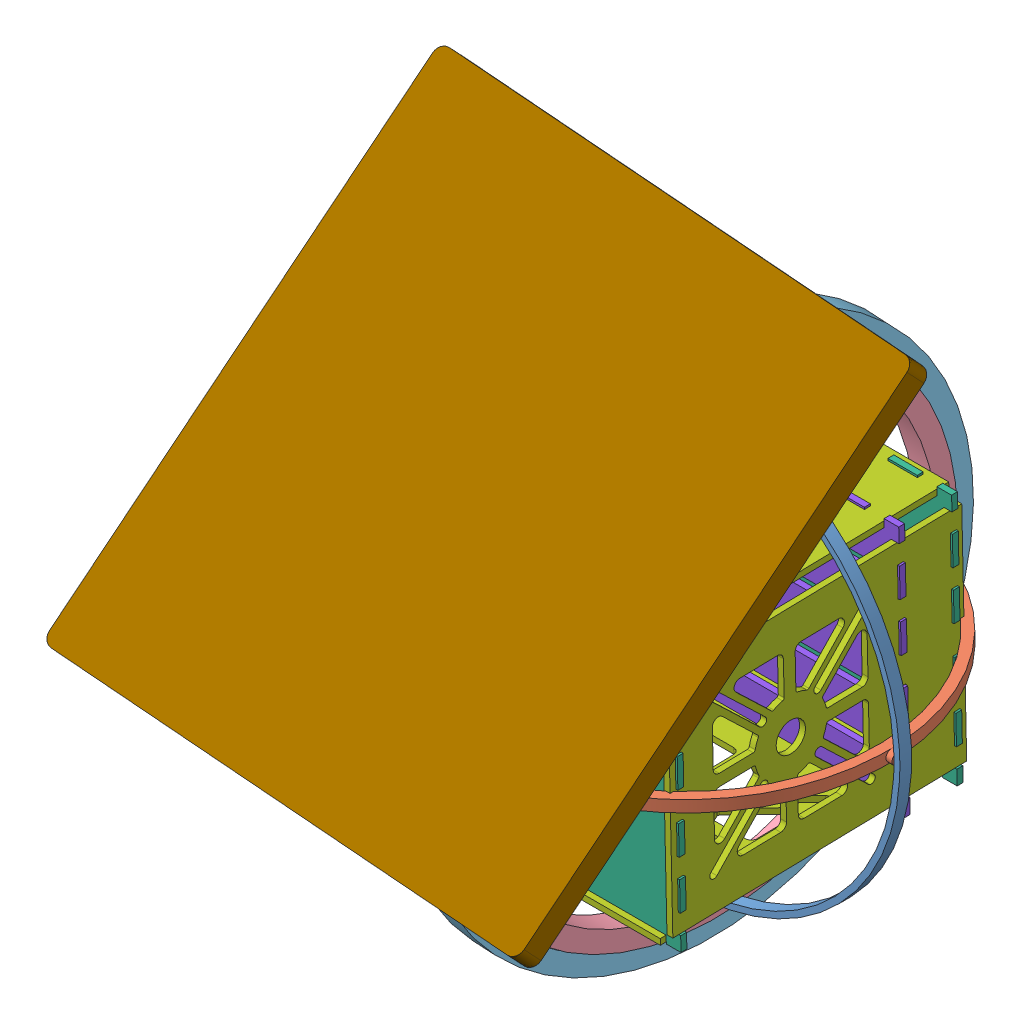
SolidWorks assembly Assem1, configuration Default. Lengths in mm.
Overall size (274.37 386.75 392.95).
17 component instances, 9 part files, 23 mates.
Components (placement in the parent):
- Part1-1: Part1 [Default] at (-77.7501 134.5326 229.0144) size (218.49 222.49 6)
- Part2-1: Part2 [Default] at (-77.7501 137.5319 232.0804) x (1 0 0) z (0 -0.999758 -0.021989) size (210.49 204.49 6)
- Part3-2: Part3 [Default] at (30.497 134.5326 232.0144) x (0 0.279636 -0.960106) z (-1 0 0) size (1 1 6)
- Part3-3: Part3 [Default] at (-179.9973 134.5326 232.0144) x (0 0.77316 -0.634211) z (-1 0 0) size (1 1 6)
- Part3-4: Part3 [Default] at (-77.7501 19.2855 232.0144) x (0.974329 0 0.225129) z (0 1 0) size (1 1 6)
- Part4-1: Part4 [Default] at (-77.7501 134.5326 232.0144) x (0.055086 0 -0.998482) z (0.998482 0 0.055086) size (246.49 246.49 12)
- Part5-1: Part5 [Default] at (-81.1914 134.5326 231.8245) x (-0.040096 -0.685716 0.726764) z (0.998482 0 0.055086) size (268.49 278.49 11.97)
- Part3-5: Part3 [Default] at (-77.7501 249.7798 232.0144) x (1 0 0) z (0 -1 0) size (1 1 6)
- final-1: final [Default] at (38.2351 129.0668 242.2567) x (0 0.999758 0.021989) z (-1 0 0) size (130 150 130)
  - shelve-1: shelve [Default] at (1.0656 79.36 115.9852) size (130 3 130)
  - sides-1: sides [Default] at (65.0656 10.36 115.9852) x (0 0 1) z (-1 0 0) size (115 150 3)
  - sides-2: sides [Default] at (-62.9344 10.36 115.9852) x (0 0 -1) z (1 0 0) size (115 150 3)
  - sides-3: sides [Default] at (1.0656 10.36 176.9852) size (115 150 3)
  - sides-4: sides [Default] at (1.0656 10.36 51.9852) size (115 150 3)
  - shelve-7: shelve [Default] at (1.0656 -61.64 115.9852) size (130 3 130)
  - shelve - Copy-1: shelve - Copy [Default] at (1.0656 52.36 115.9852) size (130 3 130)
- Part7-3: Part7 [Default] at (-86.7157 240.9814 331.9563) x (0.997727 -0.010787 0.066512) z (0.037774 -0.727869 -0.684675) size (260 260 12)
Mates (geometry in assembly coordinates):
- Concentric1: concentric: cylinder of assembly; cylinder of assembly; cylinder of Part2-1 through (27.497 134.5326 232.0144) axis (-1 0 0) radius 0.5; cylinder of Part3-2 through (24.497 134.5326 232.0144) axis (1 0 0) radius 0.5
- Coincident5: coincident: plane of assembly; circle of assembly; plane of Part1-1 through (30.497 134.5326 232.0144) normal (-1 0 0); circle of Part3-2
- Concentric9: concentric: cylinder of assembly; cylinder of assembly; cylinder of Part1-1 through (-182.9973 134.5326 232.0144) axis (-1 0 0) radius 0.5; cylinder of Part3-3 through (-185.9973 134.5326 232.0144) axis (1 0 0) radius 0.5
- Concentric10: concentric: circle of assembly; cylinder of assembly; circle of Part3-3; cylinder of Part1-1 through (-182.9973 134.5326 232.0144) axis (-1 0 0) radius 0.5
- Concentric11: concentric: circle of assembly; circle of assembly; circle of Part4-1; circle of Part5-1
- Concentric12: concentric: cylinder of assembly; cylinder of assembly; cylinder of Part1-1 through (-77.7501 245.7798 232.0144) axis (0 -1 0) radius 0.5; cylinder of Part3-5 through (-77.7501 243.7798 232.0144) axis (0 1 0) radius 0.5
- Tangent17: tangent: cylinder of assembly; plane of assembly; cylinder of Part1-1 through (-77.7501 134.5326 235.0144) axis (0 0 -1) radius 109.2472; plane of Part3-5 through (-77.7501 243.7798 232.0144) normal (0 -1 0)
- Concentric13: concentric: cylinder of assembly; cylinder of assembly; cylinder of Part1-1 through (-77.7501 23.2855 232.0144) axis (0 1 0) radius 0.5; cylinder of Part3-4 through (-77.7501 25.2855 232.0144) axis (0 -1 0) radius 0.5
- Tangent20: tangent: cylinder of assembly; plane of assembly; cylinder of Part1-1 through (-77.7501 134.5326 235.0144) axis (0 0 -1) radius 109.2472; plane of Part3-4 through (-77.7501 25.2855 232.0144) normal (0 1 0)
- Concentric14: concentric: cylinder of assembly; cylinder of assembly; cylinder of Part4-1 through (-77.7501 220.7798 232.0144) axis (0 1 0) radius 0.5; cylinder of Part3-5 through (-77.7501 243.7798 232.0144) axis (0 1 0) radius 0.5
- Concentric15: concentric: cylinder of assembly; cylinder of assembly; cylinder of Part3-4 through (-77.7501 25.2855 232.0144) axis (0 -1 0) radius 0.5; cylinder of Part4-1 through (-77.7501 30.2855 232.0144) axis (0 -1 0) radius 0.5
- Coincident6: coincident: plane of assembly; plane of assembly; plane of Part4-1 through (-77.7501 249.7798 232.0144) normal (0 -1 0); plane of Part3-5 through (-77.7501 249.7798 232.0144) normal (0 1 0)
- Tangent21: tangent: cylinder of assembly; plane of assembly; cylinder of Part2-1 through (-77.7501 131.5333 231.9484) axis (0 0.999758 0.021989) radius 102.2472; plane of Part3-2 through (24.497 134.5326 232.0144) normal (-1 0 0)
- Coincident9: coincident: plane of assembly; plane of assembly; plane of Part1-1 through (-185.9973 134.5326 232.0144) normal (1 0 0); plane of Part3-3 through (-185.9973 134.5326 232.0144) normal (-1 0 0)
- Concentric16: concentric: cylinder of assembly; cylinder of assembly; cylinder of Part2-1 through (-182.9973 134.5326 232.0144) axis (1 0 0) radius 0.5; cylinder of Part3-3 through (-185.9973 134.5326 232.0144) axis (1 0 0) radius 0.5
- Tangent22: tangent: cylinder of assembly; plane of assembly; cylinder of Part2-1 through (-77.7501 131.5333 231.9484) axis (0 0.999758 0.021989) radius 102.2472; plane of Part3-3 through (-179.9973 134.5326 232.0144) normal (1 0 0)
- Parallel2: parallel: plane of assembly; plane of assembly; plane of Part4-1 through (-71.7592 257.7798 232.3449) normal (0.998482 0 0.055086); plane of Part5-1 through (-70.5528 44.0969 147.0837) normal (0.998482 0 0.055086)
- Concentric18: concentric: cylinder of assembly; cylinder of assembly; cylinder of Part5-1 through (-86.6401 239.5257 330.5869) axis (0.037774 -0.727869 -0.684675) radius 5.975; cylinder of Part7-3 through (-86.6401 239.5257 330.5869) axis (0.037774 -0.727869 -0.684675) radius 5.795
- Coincident13: coincident: circle of assembly; plane of assembly; circle of Part5-1; plane of Part7-3 through (-86.6401 239.5257 330.5869) normal (0.037774 -0.727869 -0.684675)
- Coincident14: coincident: plane of assembly; plane of assembly; plane of Part2-1 through (-13.7501 143.1409 158.9671) normal (-1 0 0); plane of final-1/sides-4 through (-13.7501 130.36 231.9226) normal (1 0 0)
- Coincident15: coincident: plane of assembly; plane of assembly; plane of Part2-1 through (-13.7501 143.1801 157.1864) normal (0 -0.021989 0.999758); plane of final-1/sides-4 through (-16.7501 74.523 155.6764) normal (0 0.021989 -0.999758)
- Coincident16: coincident: plane of assembly; plane of assembly; plane of Part2-1 through (-141.7501 139.9209 305.3695) normal (1 0 0); plane of final-1/sides-3 through (-141.7501 130.36 231.9226) normal (-1 0 0)
- Coincident17: coincident: plane of assembly; plane of assembly; plane of Part2-1 through (-141.7501 139.8817 307.1502) normal (0 0.021989 -0.999758); plane of final-1/sides-3 through (-141.7501 71.2247 305.6401) normal (0 -0.021989 0.999758)
